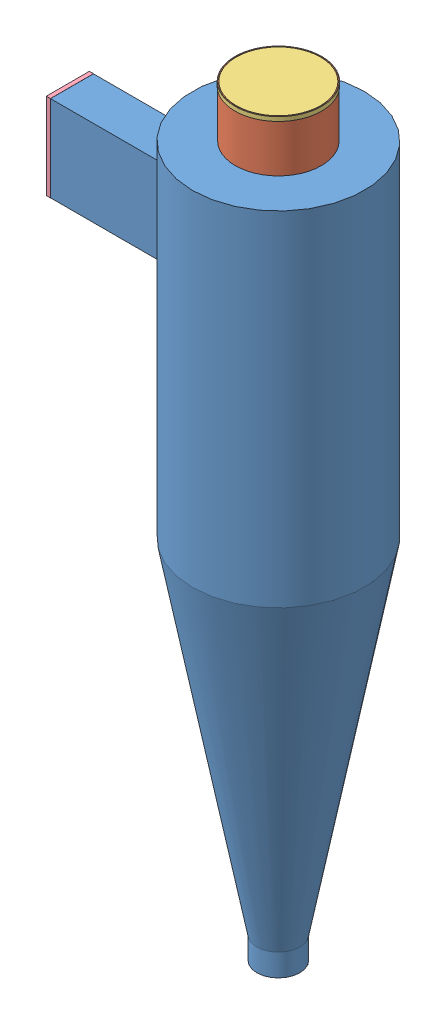
SolidWorks assembly E3_S5_AVA_E, configuration Predeterminado. Lengths in mm.
Overall size (1500 4430.01 1000).
5 component instances, 5 part files, 2 mates.
Components (placement in the parent):
- E3_S5_AVA_P1-1: E3_S5_AVA_P1 [Predeterminado] at (-312.6939 -1909.4975 4130) size (1500 4130 1000)
- E3_S5_AVA_P2-1: E3_S5_AVA_P2 [Predeterminado] at (-312.6939 2020.5025 4130) x (0.999999 0 -0.001696) z (0.001696 0 0.999999) size (500 500 500)
- LID1-1: LID1 [Predeterminado] at origin size (503.87 23.92 503.87)
- LID2-1: LID2 [Predeterminado] at origin size (23.91 500.91 250.91)
- LID3-1: LID3 [Predeterminado] at origin size (246.8 23.92 246.8)
Mates (geometry in assembly coordinates):
- Concéntrica1: concentric: circle of assembly; cylinder of assembly; circle of E3_S5_AVA_P1-1; cylinder of E3_S5_AVA_P2-1 through (-312.6939 2020.5025 4130) axis (0 -1 0) radius 250
- Distancia1: distance = 300 mm: plane of assembly; plane of assembly; plane of E3_S5_AVA_P1-1 through (-812.6939 2220.5025 4130) normal (0 1 0); plane of E3_S5_AVA_P2-1 through (-562.6936 2520.5025 4130.4241) normal (0 1 0)
